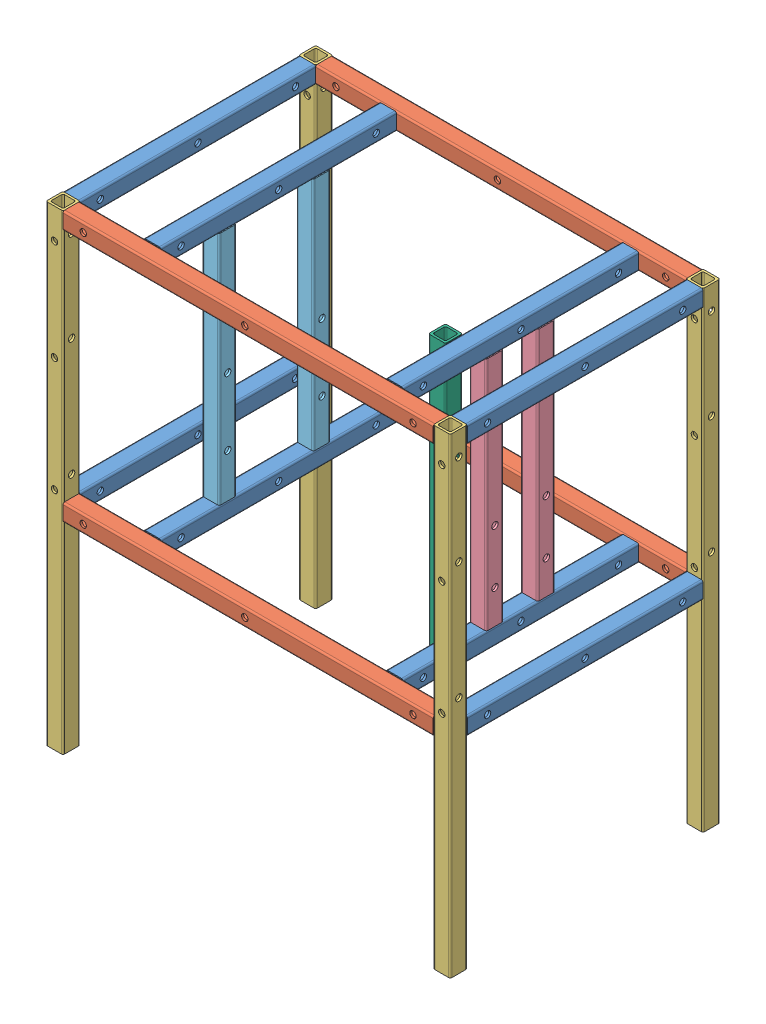
SolidWorks assembly Estructuraensamblada, configuration Predeterminado. Lengths in mm.
Overall size (600.8 700 400.8).
21 component instances, 6 part files, 61 mates.
Components (placement in the parent):
- PTR - FRENTESBARRENADOS-1: PTR - FRENTESBARRENADOS [Predeterminado] at (-3.8926 1.1998 175) size (25.4 25.4 350)
- PTR - LADOS-1: PTR - LADOS [Predeterminado] at (8.8074 1.1998 162.3) x (0 0 -1) z (1 0 0) size (25.4 25.4 550)
- PTR - PATAS-1: PTR - PATAS [Predeterminado] at (-3.8926 -686.1002 162.3) x (1 0 0) z (0 1 0) size (25.4 25.4 700)
- PTR - FRENTESBARRENADOS-2: PTR - FRENTESBARRENADOS [Predeterminado] at (571.5074 1.1998 175) size (25.4 25.4 350)
- PTR - FRENTESBARRENADOS-3: PTR - FRENTESBARRENADOS [Predeterminado] at (-3.8926 -374.2002 175) size (25.4 25.4 350)
- PTR - FRENTESBARRENADOS-4: PTR - FRENTESBARRENADOS [Predeterminado] at (571.5074 -374.2002 175) size (25.4 25.4 350)
- PTR - PATAS-2: PTR - PATAS [Predeterminado] at (571.5074 -686.1002 537.7) x (1 0 0) z (0 1 0) size (25.4 25.4 700)
- PTR - PATAS-3: PTR - PATAS [Predeterminado] at (571.5074 -686.1002 162.3) x (1 0 0) z (0 1 0) size (25.4 25.4 700)
- PTR - PATAS-4: PTR - PATAS [Predeterminado] at (-3.8926 -686.1002 537.7) x (1 0 0) z (0 1 0) size (25.4 25.4 700)
- PTR - LADOS-2: PTR - LADOS [Predeterminado] at (8.8074 1.1998 537.7) x (0 0 -1) z (1 0 0) size (25.4 25.4 550)
- PTR - LADOS-3: PTR - LADOS [Predeterminado] at (8.8074 -374.2002 537.7) x (0 0 -1) z (1 0 0) size (25.4 25.4 550)
- PTR - LADOS-4: PTR - LADOS [Predeterminado] at (8.8074 -374.2002 162.3) x (0 0 -1) z (1 0 0) size (25.4 25.4 550)
- PTR - CHUMACERAS-1: PTR - CHUMACERAS [Predeterminado] at (476.1074 -361.5002 312.3) x (1 0 0) z (0 1 0) size (25.4 25.4 350)
- PTR - MOTOR-1: PTR - MOTOR [Predeterminado] at (116.1074 -361.5002 425.7) x (1 0 0) z (0 1 0) size (25.4 25.4 350)
- PTR - SOPLETE-1: PTR - SOPLETE [Predeterminado] at (450.7074 13.8998 424.1) x (-1 0 0) z (0 -1 0) size (25.4 25.4 400)
- PTR - FRENTESBARRENADOS-5: PTR - FRENTESBARRENADOS [Predeterminado] at (116.1074 1.1998 175) size (25.4 25.4 350)
- PTR - FRENTESBARRENADOS-6: PTR - FRENTESBARRENADOS [Predeterminado] at (476.1074 1.1998 175) size (25.4 25.4 350)
- PTR - FRENTESBARRENADOS-7: PTR - FRENTESBARRENADOS [Predeterminado] at (476.1074 -374.2002 175) size (25.4 25.4 350)
- PTR - FRENTESBARRENADOS-8: PTR - FRENTESBARRENADOS [Predeterminado] at (116.1074 -374.2002 175) size (25.4 25.4 350)
- PTR - CHUMACERAS-2: PTR - CHUMACERAS [Predeterminado] at (476.1074 -361.5002 388.7) x (1 0 0) z (0 1 0) size (25.4 25.4 350)
- PTR - MOTOR-2: PTR - MOTOR [Predeterminado] at (116.1074 -361.5002 285.7) x (1 0 0) z (0 1 0) size (25.4 25.4 350)
Mates (geometry in assembly coordinates):
- Coincidente1: coincident aligned: plane of PTR - FRENTESBARRENADOS-1 through (-16.5926 -9.0002 525) normal (-1 0 0); plane of PTR - PATAS-1 through (-16.5926 13.8998 172.5) normal (-1 0 0)
- Coincidente2: coincident aligned: plane of PTR - FRENTESBARRENADOS-1 through (-14.0926 13.8998 525) normal (0 1 0); plane of PTR - PATAS-1 through (6.3074 13.8998 172.5) normal (0 1 0)
- Coincidente3: coincident anti-aligned: plane of PTR - FRENTESBARRENADOS-1 through (6.3074 -9.0002 175) normal (0 0 -1); plane of PTR - PATAS-1 through (-14.0926 13.8998 175) normal (0 0 1)
- Coincidente5: coincident aligned: plane of PTR - FRENTESBARRENADOS-1 through (-14.0926 13.8998 525) normal (0 1 0); plane of PTR - LADOS-1 through (558.8074 13.8998 172.5) normal (0 1 0)
- Coincidente6: coincident aligned: plane of PTR - LADOS-1 through (558.8074 -9.0002 149.6) normal (0 0 -1); plane of PTR - PATAS-1 through (-14.0926 13.8998 149.6) normal (0 0 -1)
- Coincidente7: coincident anti-aligned: plane of PTR - LADOS-1 through (8.8074 -9.0002 152.1) normal (-1 0 0); plane of PTR - PATAS-1 through (8.8074 13.8998 172.5) normal (1 0 0)
- Coincidente8: coincident aligned: plane of PTR - FRENTESBARRENADOS-1 through (-16.5926 -9.0002 525) normal (-1 0 0); plane of PTR - FRENTESBARRENADOS-3 through (-16.5926 -384.4002 525) normal (-1 0 0)
- Coincidente9: coincident aligned: plane of PTR - FRENTESBARRENADOS-3 through (-14.0926 -361.5002 525) normal (0 1 0); plane of PTR - FRENTESBARRENADOS-4 through (561.3074 -361.5002 525) normal (0 1 0)
- Coincidente10: coincident aligned: plane of PTR - FRENTESBARRENADOS-1 through (-14.0926 13.8998 525) normal (0 1 0); plane of PTR - FRENTESBARRENADOS-2 through (561.3074 13.8998 525) normal (0 1 0)
- Coincidente11: coincident aligned: plane of PTR - FRENTESBARRENADOS-2 through (558.8074 -9.0002 525) normal (-1 0 0); plane of PTR - FRENTESBARRENADOS-4 through (558.8074 -384.4002 525) normal (-1 0 0)
- Ancho1: width aligned: plane of PTR - FRENTESBARRENADOS-1 through (6.3074 -9.0002 525) normal (0 0 1); plane of PTR - FRENTESBARRENADOS-3 through (581.7074 -9.0002 525) normal (0 0 1); plane of PTR - FRENTESBARRENADOS-2 through (6.3074 -384.4002 525) normal (0 0 1); plane of PTR - FRENTESBARRENADOS-4 through (581.7074 -384.4002 525) normal (0 0 1)
- Coincidente12: coincident aligned: plane of PTR - PATAS-1 through (-14.0926 13.8998 149.6) normal (0 0 -1); plane of PTR - PATAS-3 through (561.3074 13.8998 149.6) normal (0 0 -1)
- Coincidente13: coincident aligned: plane of PTR - FRENTESBARRENADOS-1 through (-14.0926 13.8998 525) normal (0 1 0); plane of PTR - PATAS-3 through (581.7074 13.8998 172.5) normal (0 1 0)
- Coincidente14: coincident anti-aligned: plane of PTR - LADOS-1 through (558.8074 -9.0002 152.1) normal (1 0 0); plane of PTR - PATAS-3 through (558.8074 13.8998 172.5) normal (-1 0 0)
- Coincidente15: coincident aligned: plane of PTR - PATAS-1 through (-16.5926 13.8998 172.5) normal (-1 0 0); plane of PTR - PATAS-4 through (-16.5926 13.8998 547.9) normal (-1 0 0)
- Coincidente16: coincident aligned: plane of PTR - FRENTESBARRENADOS-1 through (-14.0926 13.8998 525) normal (0 1 0); plane of PTR - PATAS-4 through (6.3074 13.8998 547.9) normal (0 1 0)
- Coincidente17: coincident anti-aligned: plane of PTR - FRENTESBARRENADOS-1 through (6.3074 -9.0002 525) normal (0 0 1); plane of PTR - PATAS-4 through (-14.0926 13.8998 525) normal (0 0 -1)
- Coincidente18: coincident aligned: plane of PTR - FRENTESBARRENADOS-2 through (584.2074 -9.0002 525) normal (1 0 0); plane of PTR - PATAS-3 through (584.2074 13.8998 172.5) normal (1 0 0)
- Coincidente19: coincident anti-aligned: plane of PTR - FRENTESBARRENADOS-2 through (581.7074 -9.0002 175) normal (0 0 -1); plane of PTR - PATAS-3 through (561.3074 13.8998 175) normal (0 0 1)
- Coincidente20: coincident aligned: plane of PTR - FRENTESBARRENADOS-2 through (561.3074 13.8998 525) normal (0 1 0); plane of PTR - PATAS-2 through (581.7074 13.8998 547.9) normal (0 1 0)
- Coincidente21: coincident aligned: plane of PTR - FRENTESBARRENADOS-2 through (584.2074 -9.0002 525) normal (1 0 0); plane of PTR - PATAS-2 through (584.2074 13.8998 547.9) normal (1 0 0)
- Coincidente22: coincident anti-aligned: plane of PTR - FRENTESBARRENADOS-2 through (581.7074 -9.0002 525) normal (0 0 1); plane of PTR - PATAS-2 through (561.3074 13.8998 525) normal (0 0 -1)
- Coincidente23: coincident anti-aligned: plane of PTR - FRENTESBARRENADOS-4 through (581.7074 -384.4002 175) normal (0 0 -1); plane of PTR - PATAS-3 through (561.3074 13.8998 175) normal (0 0 1)
- Coincidente24: coincident aligned: plane of PTR - FRENTESBARRENADOS-4 through (584.2074 -384.4002 525) normal (1 0 0); plane of PTR - PATAS-2 through (584.2074 13.8998 547.9) normal (1 0 0)
- Coincidente25: coincident aligned: plane of PTR - LADOS-1 through (558.8074 13.8998 172.5) normal (0 1 0); plane of PTR - LADOS-2 through (558.8074 13.8998 547.9) normal (0 1 0)
- Coincidente26: coincident anti-aligned: plane of PTR - FRENTESBARRENADOS-1 through (8.8074 -9.0002 525) normal (1 0 0); plane of PTR - LADOS-2 through (8.8074 -9.0002 527.5) normal (-1 0 0)
- Coincidente27: coincident aligned: plane of PTR - PATAS-4 through (-14.0926 13.8998 550.4) normal (0 0 1); plane of PTR - LADOS-2 through (558.8074 -9.0002 550.4) normal (0 0 1)
- Coincidente28: coincident aligned: plane of PTR - LADOS-3 through (558.8074 -361.5002 547.9) normal (0 1 0); plane of PTR - LADOS-4 through (558.8074 -361.5002 172.5) normal (0 1 0)
- Coincidente29: coincident aligned: plane of PTR - LADOS-3 through (558.8074 -384.4002 527.5) normal (1 0 0); plane of PTR - LADOS-4 through (558.8074 -384.4002 152.1) normal (1 0 0)
- Coincidente30: coincident aligned: plane of PTR - PATAS-2 through (561.3074 13.8998 525) normal (0 0 -1); plane of PTR - LADOS-3 through (558.8074 -384.4002 525) normal (0 0 -1)
- Coincidente31: coincident aligned: plane of PTR - PATAS-3 through (561.3074 13.8998 149.6) normal (0 0 -1); plane of PTR - LADOS-4 through (558.8074 -384.4002 149.6) normal (0 0 -1)
- Coincidente32: coincident aligned: plane of PTR - FRENTESBARRENADOS-4 through (561.3074 -361.5002 525) normal (0 1 0); plane of PTR - LADOS-4 through (558.8074 -361.5002 172.5) normal (0 1 0)
- Coincidente33: coincident anti-aligned: plane of PTR - PATAS-1 through (8.8074 13.8998 172.5) normal (1 0 0); plane of PTR - LADOS-4 through (8.8074 -384.4002 152.1) normal (-1 0 0)
- Coincidente34: coincident aligned: plane of PTR - FRENTESBARRENADOS-5 through (105.9074 13.8998 525) normal (0 1 0); plane of PTR - FRENTESBARRENADOS-6 through (465.9074 13.8998 525) normal (0 1 0)
- Coincidente35: coincident aligned: plane of PTR - FRENTESBARRENADOS-5 through (126.3074 -9.0002 175) normal (0 0 -1); plane of PTR - FRENTESBARRENADOS-6 through (486.3074 -9.0002 175) normal (0 0 -1)
- Coincidente36: coincident aligned: plane of PTR - FRENTESBARRENADOS-7 through (465.9074 -361.5002 525) normal (0 1 0); plane of PTR - FRENTESBARRENADOS-8 through (105.9074 -361.5002 525) normal (0 1 0)
- Coincidente37: coincident aligned: plane of PTR - FRENTESBARRENADOS-7 through (486.3074 -384.4002 175) normal (0 0 -1); plane of PTR - FRENTESBARRENADOS-8 through (126.3074 -384.4002 175) normal (0 0 -1)
- Coincidente38: coincident aligned: plane of PTR - LADOS-4 through (558.8074 -361.5002 172.5) normal (0 1 0); plane of PTR - FRENTESBARRENADOS-7 through (465.9074 -361.5002 525) normal (0 1 0)
- Coincidente39: coincident anti-aligned: plane of PTR - LADOS-4 through (558.8074 -384.4002 175) normal (0 0 1); plane of PTR - FRENTESBARRENADOS-7 through (486.3074 -384.4002 175) normal (0 0 -1)
- Coincidente40: coincident anti-aligned: plane of PTR - LADOS-1 through (558.8074 -9.0002 175) normal (0 0 1); plane of PTR - FRENTESBARRENADOS-5 through (126.3074 -9.0002 175) normal (0 0 -1)
- Coincidente41: coincident aligned: plane of PTR - LADOS-1 through (558.8074 13.8998 172.5) normal (0 1 0); plane of PTR - FRENTESBARRENADOS-5 through (105.9074 13.8998 525) normal (0 1 0)
- Coincidente42: coincident aligned: plane of PTR - FRENTESBARRENADOS-6 through (463.4074 -9.0002 525) normal (-1 0 0); plane of PTR - FRENTESBARRENADOS-7 through (463.4074 -384.4002 525) normal (-1 0 0)
- Coincidente43: coincident aligned: plane of PTR - FRENTESBARRENADOS-5 through (103.4074 -9.0002 525) normal (-1 0 0); plane of PTR - FRENTESBARRENADOS-8 through (103.4074 -384.4002 525) normal (-1 0 0)
- Coincidente44: coincident aligned: plane of PTR - MOTOR-1 through (103.4074 -11.5002 435.9) normal (-1 0 0); plane of PTR - FRENTESBARRENADOS-8 through (103.4074 -384.4002 525) normal (-1 0 0)
- Coincidente45: coincident anti-aligned: plane of PTR - MOTOR-1 through (126.3074 -11.5002 435.9) normal (0 1 0); plane of PTR - FRENTESBARRENADOS-5 through (105.9074 -11.5002 525) normal (0 -1 0)
- Coincidente46: coincident anti-aligned: plane of PTR - MOTOR-1 through (126.3074 -361.5002 435.9) normal (0 -1 0); plane of PTR - FRENTESBARRENADOS-8 through (105.9074 -361.5002 525) normal (0 1 0)
- Coincidente47: coincident anti-aligned: plane of PTR - CHUMACERAS-1 through (486.3074 -11.5002 327.7474) normal (0 1 0); plane of PTR - FRENTESBARRENADOS-6 through (465.9074 -11.5002 525) normal (0 -1 0)
- Coincidente48: coincident aligned: plane of PTR - CHUMACERAS-1 through (463.4074 -11.5002 327.7474) normal (-1 0 0); plane of PTR - FRENTESBARRENADOS-7 through (463.4074 -384.4002 525) normal (-1 0 0)
- Coincidente49: coincident aligned: plane of PTR - SOPLETE-1 through (440.5074 13.8998 439.5474) normal (0 1 0); plane of PTR - FRENTESBARRENADOS-6 through (465.9074 13.8998 525) normal (0 1 0)
- Coincidente50: coincident anti-aligned: plane of PTR - SOPLETE-1 through (463.4074 -386.1002 439.5474) normal (1 0 0); plane of PTR - FRENTESBARRENADOS-6 through (463.4074 -9.0002 525) normal (-1 0 0)
- Coincidente51: coincident anti-aligned: plane of PTR - FRENTESBARRENADOS-6 through (465.9074 -11.5002 525) normal (0 -1 0); plane of PTR - CHUMACERAS-2 through (486.3074 -11.5002 404.1474) normal (0 1 0)
- Coincidente52: coincident aligned: plane of PTR - CHUMACERAS-1 through (463.4074 -11.5002 327.7474) normal (-1 0 0); plane of PTR - CHUMACERAS-2 through (463.4074 -11.5002 404.1474) normal (-1 0 0)
- Coincidente53: coincident aligned: plane of PTR - MOTOR-1 through (126.3074 -11.5002 435.9) normal (0 1 0); plane of PTR - MOTOR-2 through (126.3074 -11.5002 295.9) normal (0 1 0)
- Coincidente54: coincident aligned: plane of PTR - FRENTESBARRENADOS-5 through (103.4074 -9.0002 525) normal (-1 0 0); plane of PTR - MOTOR-2 through (103.4074 -11.5002 295.9) normal (-1 0 0)
- Distancia1: distance = 70 mm anti-aligned: plane of PTR - FRENTESBARRENADOS-6 through (488.8074 -9.0002 525) normal (1 0 0); plane of PTR - FRENTESBARRENADOS-2 through (558.8074 -9.0002 525) normal (-1 0 0)
- Distancia2: distance = 120 mm aligned: plane of PTR - FRENTESBARRENADOS-5 through (128.8074 -9.0002 525) normal (1 0 0); plane of PTR - FRENTESBARRENADOS-1 through (8.8074 -9.0002 525) normal (1 0 0)
- Distancia3: distance = 51 mm anti-aligned: plane of PTR - CHUMACERAS-2 through (465.9074 -11.5002 376) normal (0 0 -1); plane of PTR - CHUMACERAS-1 through (465.9074 -11.5002 325) normal (0 0 1)
- Distancia4: distance = 10 mm anti-aligned: plane of PTR - SOPLETE-1 through (460.9074 -386.1002 411.4) normal (0 0 -1); plane of PTR - CHUMACERAS-2 through (465.9074 -11.5002 401.4) normal (0 0 1)
- Distancia5: distance = 140 mm aligned: plane of PTR - MOTOR-2 through (105.9074 -11.5002 298.4) normal (0 0 1); plane of PTR - MOTOR-1 through (105.9074 -11.5002 438.4) normal (0 0 1)
- Distancia6: distance = 112 mm aligned: plane of PTR - MOTOR-1 through (105.9074 -11.5002 438.4) normal (0 0 1); plane of PTR - PATAS-4 through (-14.0926 13.8998 550.4) normal (0 0 1)
- Distancia7: distance = 150 mm aligned: plane of PTR - CHUMACERAS-1 through (465.9074 -11.5002 299.6) normal (0 0 -1); plane of PTR - PATAS-3 through (561.3074 13.8998 149.6) normal (0 0 -1)
